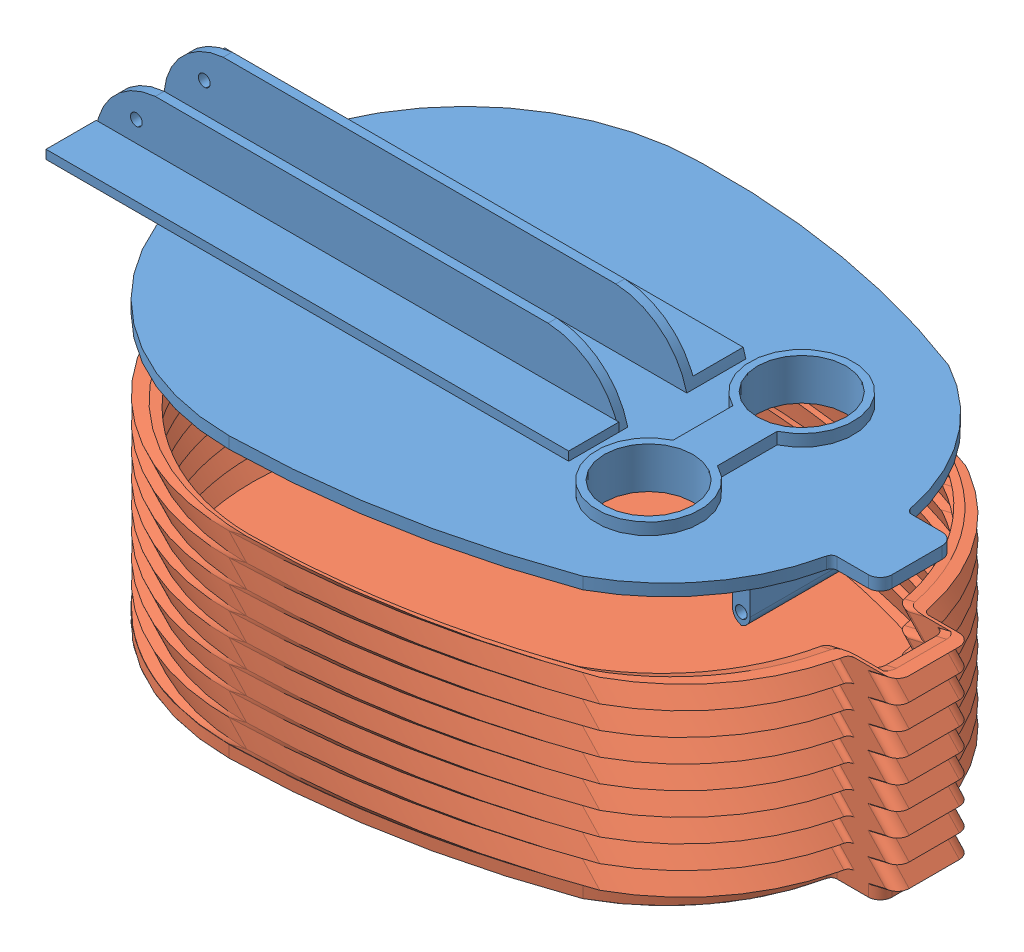
SolidWorks assembly Assem1, configuration Default. Lengths in mm.
Overall size (270.82 114.76 167.7).
2 component instances, 2 part files, 4 mates.
Components (placement in the parent):
- tapa sup de fuelle-1: tapa sup de fuelle [Default] at (-30.2223 40.2489 8.7587) size (265 43.89 160.08)
- tapa de fuelle-2: tapa de fuelle [Default] at (-30.2223 -50.3326 8.7587) size (242.01 71.65 167.7)
Mates (geometry in assembly coordinates):
- Coincident1: coincident: plane of ? through (106.622 -24.7432 -8.6799) normal (1 0 0); plane of tapa sup de fuelle-1 through (106.622 44.2489 -8.6799) normal (1 0 0)
- Coincident2: coincident: plane of ? through (102.622 -24.7432 12.3201) normal (0 0 1); plane of tapa sup de fuelle-1 through (102.622 44.2489 12.3201) normal (0 0 1)
- Coincident3: coincident: plane of tapa sup de fuelle-1 through (94.7777 44.2489 0.2587) normal (1 0 0); plane of tapa de fuelle-2 through (94.7777 -46.3326 0.2587) normal (1 0 0)
- Coincident4: coincident: plane of tapa sup de fuelle-1 through (90.7777 44.2489 21.2587) normal (0 0 1); plane of tapa de fuelle-2 through (90.7777 -46.3326 21.2587) normal (0 0 1)
